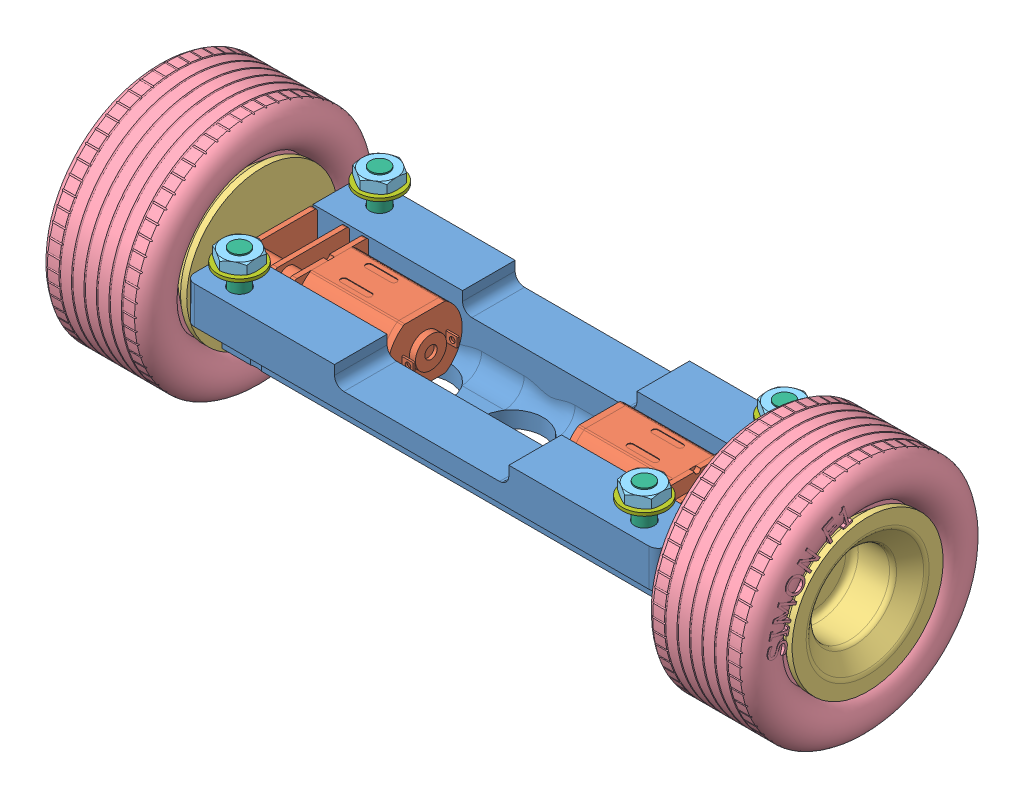
SolidWorks assembly Assembly wiel, configuration Default. Lengths in mm.
Overall size (115.21 38 38).
19 component instances, 7 part files, 51 mates.
Components (placement in the parent):
- Motor mount-1: Motor mount [Default] at origin size (76 12.7 29)
- Micro Metal Gear Motor-1: Micro Metal Gear Motor [Default] at (29 -5.04 0) x (0 0 -1) z (1 0 0) size (12 10 35.9)
- Micro Metal Gear Motor-2: Micro Metal Gear Motor [Default] at (-29 -5.04 0) x (0 0 1) z (-1 0 0) size (12 10 35.9)
- Velg-1: Velg [Default] at (-48.6 -5.04 0) x (1 0 0) z (0 -1 0) size (17 24.25 24.25)
- Velg-2: Velg [Default] at (48.6 -5.04 0) x (-1 0 0) z (0 -1 0) size (17 24.25 24.25)
- Band-1: Band [Default] at (48.6 -5.04 0) x (1 0 0) z (0 1 0) size (18 38 38)
- Band-2: Band [Default] at (-48.6 -5.04 0) x (-1 0 0) z (0 1 0) size (18 38 38)
- hex thin nut chamfered gradeab_iso-1: hex thin nut chamfered gradeab_iso [ISO - 4035 - M3 - N] at (32.5 5.3 -11.25) x (0.5 0 0.866025) z (0 1 0) size (5.5 6.35 1.8)
- hex thin nut chamfered gradeab_iso-2: hex thin nut chamfered gradeab_iso [ISO - 4035 - M3 - N] at (-32.5 5.3 11.25) x (0.5 0 -0.866025) z (0 1 0) size (5.5 6.35 1.8)
- pan head cross recess screw_iso-1: pan head cross recess screw_iso [ISO 7045 - M3 x 10 - Z - 10N] at (32.5 -6.9 11.25) x (0 1 0) z (-1 0 0) size (12.35 5.6 5.6)
- pan head cross recess screw_iso-2: pan head cross recess screw_iso [ISO 7045 - M3 x 10 - Z - 10N] at (32.5 -6.9 -11.25) x (0 1 0) z (-1 0 0) size (12.35 5.6 5.6)
- pan head cross recess screw_iso-3: pan head cross recess screw_iso [ISO 7045 - M3 x 10 - Z - 10N] at (-32.5 -6.9 11.25) x (0 1 0) z (-1 0 0) size (12.35 5.6 5.6)
- pan head cross recess screw_iso-4: pan head cross recess screw_iso [ISO 7045 - M3 x 10 - Z - 10N] at (-32.5 -6.9 -11.25) x (0 1 0) z (-1 0 0) size (12.35 5.6 5.6)
- hex thin nut chamfered gradeab_iso-3: hex thin nut chamfered gradeab_iso [ISO - 4035 - M3 - N] at (-32.5 5.3 -11.25) x (-0.5 0 -0.866025) z (0 1 0) size (5.5 6.35 1.8)
- hex thin nut chamfered gradeab_iso-4: hex thin nut chamfered gradeab_iso [ISO - 4035 - M3 - N] at (32.5 3.5 11.25) x (1 0 0) z (0 -1 0) size (5.5 6.35 1.8)
- plain washer normal grade a_iso-1: plain washer normal grade a_iso [Washer ISO 7089 - 3] at (32.5 3 -11.25) x (0 -1 0) z (-1 0 0) size (0.5 7 7)
- plain washer normal grade a_iso-2: plain washer normal grade a_iso [Washer ISO 7089 - 3] at (32.5 3 11.25) x (0 -1 0) z (-1 0 0) size (0.5 7 7)
- plain washer normal grade a_iso-3: plain washer normal grade a_iso [Washer ISO 7089 - 3] at (-32.5 3 11.25) x (0 -1 0) z (-1 0 0) size (0.5 7 7)
- plain washer normal grade a_iso-4: plain washer normal grade a_iso [Washer ISO 7089 - 3] at (-32.5 3 -11.25) x (0 -1 0) z (-1 0 0) size (0.5 7 7)
Mates (geometry in assembly coordinates):
- Coincident32: coincident aligned: plane of Motor mount-1 through (0 0 0) normal (1 0 0)
- Coincident33: coincident aligned: plane of Motor mount-1 through (0 0 0) normal (0 0 1)
- Coincident35: coincident aligned: plane of Motor mount-1 through (0 0 0) normal (0 1 0)
- Concentric17: concentric aligned: cylinder of Motor mount-1 through (32.5 0 -11.25) axis (0 -1 0) radius 1.5875; cylinder of pan head cross recess screw_iso-2 through (32.5 -32.3 -11.25) axis (0 -1 0) radius 1.5
- Concentric18: concentric aligned: cylinder of Motor mount-1 through (32.5 0 11.25) axis (0 -1 0) radius 1.5875; cylinder of pan head cross recess screw_iso-1 through (32.5 -32.3 11.25) axis (0 -1 0) radius 1.5
- Concentric19: concentric aligned: cylinder of Motor mount-1 through (-32.5 0 11.25) axis (0 -1 0) radius 1.5875; cylinder of pan head cross recess screw_iso-3 through (-32.5 -32.3 11.25) axis (0 -1 0) radius 1.5
- Concentric20: concentric aligned: cylinder of Motor mount-1 through (-32.5 0 -11.25) axis (0 -1 0) radius 1.5875; cylinder of pan head cross recess screw_iso-4 through (-32.5 -32.3 -11.25) axis (0 -1 0) radius 1.5
- Coincident36: coincident aligned: plane of pan head cross recess screw_iso-1 through (32.5 -4.5 9.75) normal (0 1 0); plane of pan head cross recess screw_iso-2 through (32.5 -4.5 -12.75) normal (0 1 0)
- Coincident37: coincident aligned: plane of pan head cross recess screw_iso-1 through (32.5 -4.5 9.75) normal (0 1 0); plane of pan head cross recess screw_iso-3 through (-32.5 -4.5 9.75) normal (0 1 0)
- Coincident38: coincident aligned: plane of pan head cross recess screw_iso-2 through (32.5 -4.5 -12.75) normal (0 1 0); plane of pan head cross recess screw_iso-4 through (-32.5 -4.5 -12.75) normal (0 1 0)
- Coincident39: coincident aligned: plane of pan head cross recess screw_iso-1 through (32.13 -5.15 11.7775) normal (1 0 0); plane of pan head cross recess screw_iso-2 through (32.13 -5.15 -10.7225) normal (1 0 0)
- Coincident40: coincident aligned: plane of pan head cross recess screw_iso-3 through (-32.87 -5.15 11.7775) normal (1 0 0); plane of pan head cross recess screw_iso-4 through (-32.87 -5.15 -10.7225) normal (1 0 0)
- Coincident41: coincident anti-aligned: plane of Motor mount-1 through (-32.5 -4.5 -11.25) normal (0 -1 0); plane of pan head cross recess screw_iso-4 through (-32.5 -4.5 -12.75) normal (0 1 0)
- Coincident42: coincident aligned: plane of hex thin nut chamfered gradeab_iso-1 through (35.25 3.5 -12.8377) normal (0 -1 0); plane of hex thin nut chamfered gradeab_iso-4 through (32.5 3.5 14.4254) normal (0 -1 0)
- Coincident43: coincident aligned: plane of hex thin nut chamfered gradeab_iso-1 through (35.25 3.5 -12.8377) normal (0 -1 0); plane of hex thin nut chamfered gradeab_iso-2 through (-35.25 3.5 9.6623) normal (0 -1 0)
- Coincident44: coincident aligned: plane of hex thin nut chamfered gradeab_iso-2 through (-35.25 3.5 9.6623) normal (0 -1 0); plane of hex thin nut chamfered gradeab_iso-3 through (-35.25 3.5 -9.6623) normal (0 -1 0)
- Coincident45: coincident aligned: plane of hex thin nut chamfered gradeab_iso-1 through (29.75 3.5 -12.8377) normal (-1 0 0); plane of hex thin nut chamfered gradeab_iso-4 through (29.75 5.3 12.8377) normal (-1 0 0)
- Coincident46: coincident aligned: plane of hex thin nut chamfered gradeab_iso-2 through (-35.25 3.5 9.6623) normal (-1 0 0); plane of hex thin nut chamfered gradeab_iso-3 through (-35.25 3.5 -12.8377) normal (-1 0 0)
- Concentric21: concentric aligned: cylinder of pan head cross recess screw_iso-1 through (32.5 -32.3 11.25) axis (0 -1 0) radius 1.5; cylinder of hex thin nut chamfered gradeab_iso-4 through (32.5 5.3 11.25) axis (0 -1 0) radius 1.25
- Concentric22: concentric anti-aligned: cylinder of hex thin nut chamfered gradeab_iso-1 through (32.5 3.5 -11.25) axis (0 1 0) radius 1.25; cylinder of pan head cross recess screw_iso-2 through (32.5 -32.3 -11.25) axis (0 -1 0) radius 1.5
- Concentric23: concentric anti-aligned: cylinder of hex thin nut chamfered gradeab_iso-2 through (-32.5 3.5 11.25) axis (0 1 0) radius 1.25; cylinder of pan head cross recess screw_iso-3 through (-32.5 -32.3 11.25) axis (0 -1 0) radius 1.5
- Concentric24: concentric anti-aligned: cylinder of pan head cross recess screw_iso-4 through (-32.5 -32.3 -11.25) axis (0 -1 0) radius 1.5; cylinder of hex thin nut chamfered gradeab_iso-3 through (-32.5 3.5 -11.25) axis (0 1 0) radius 1.25
- Coincident48: coincident aligned: plane of plain washer normal grade a_iso-2 through (32.5 3.5 14.75) normal (0 1 0); plane of plain washer normal grade a_iso-3 through (-32.5 3.5 14.75) normal (0 1 0)
- Coincident49: coincident aligned: plane of plain washer normal grade a_iso-1 through (32.5 3.5 -7.75) normal (0 1 0); plane of plain washer normal grade a_iso-4 through (-32.5 3.5 -7.75) normal (0 1 0)
- Coincident50: coincident aligned: plane of plain washer normal grade a_iso-1 through (32.5 3 -11.25) normal (-1 0 0); plane of plain washer normal grade a_iso-2 through (32.5 3 11.25) normal (-1 0 0)
- Coincident51: coincident aligned: plane of plain washer normal grade a_iso-3 through (-32.5 3 11.25) normal (-1 0 0); plane of plain washer normal grade a_iso-4 through (-32.5 3 -11.25) normal (-1 0 0)
- Coincident52: coincident aligned: plane of plain washer normal grade a_iso-3 through (-32.5 3.5 14.75) normal (0 1 0); plane of plain washer normal grade a_iso-4 through (-32.5 3.5 -7.75) normal (0 1 0)
- Concentric25: concentric anti-aligned: cylinder of pan head cross recess screw_iso-3 through (-32.5 -32.3 11.25) axis (0 -1 0) radius 1.5; cylinder of plain washer normal grade a_iso-3 through (-32.5 37.925 11.25) axis (0 1 0) radius 1.6
- Concentric26: concentric anti-aligned: cylinder of pan head cross recess screw_iso-4 through (-32.5 -32.3 -11.25) axis (0 -1 0) radius 1.5; cylinder of plain washer normal grade a_iso-4 through (-32.5 37.925 -11.25) axis (0 1 0) radius 1.6
- Concentric27: concentric anti-aligned: cylinder of pan head cross recess screw_iso-1 through (32.5 -32.3 11.25) axis (0 -1 0) radius 1.5; cylinder of plain washer normal grade a_iso-2 through (32.5 37.925 11.25) axis (0 1 0) radius 1.6
- Concentric28: concentric anti-aligned: cylinder of pan head cross recess screw_iso-2 through (32.5 -32.3 -11.25) axis (0 -1 0) radius 1.5; cylinder of plain washer normal grade a_iso-1 through (32.5 37.925 -11.25) axis (0 1 0) radius 1.6
- Distance2: distance = 3 mm anti-aligned: plane of plain washer normal grade a_iso-3 through (-32.5 3 12.85) normal (0 -1 0); plane of Motor mount-1 through (38 0 14.5) normal (0 1 0)
- Coincident54: coincident anti-aligned: plane of hex thin nut chamfered gradeab_iso-3 through (-35.25 3.5 -9.6623) normal (0 -1 0); plane of plain washer normal grade a_iso-4 through (-32.5 3.5 -7.75) normal (0 1 0)
- Concentric29: concentric anti-aligned: cylinder of Micro Metal Gear Motor-1 through (48.1 -5.04 0) axis (-1 0 0) radius 1.5; cylinder of Micro Metal Gear Motor-2 through (-48.1 -5.04 0) axis (1 0 0) radius 1.5
- Coincident55: coincident aligned: plane of Motor mount-1 through (38 0 0) normal (1 0 0); plane of Micro Metal Gear Motor-1 through (38 -9.54 5.5) normal (1 0 0)
- Coincident56: coincident aligned: plane of Motor mount-1 through (-38 0 0) normal (-1 0 0); plane of Micro Metal Gear Motor-2 through (-38 -9.54 -5.5) normal (-1 0 0)
- Coincident62: coincident aligned: plane of Micro Metal Gear Motor-2 through (-29 -5.04 0) normal (0 0 1)
- Coincident63: coincident: point of Motor mount-1; plane of Micro Metal Gear Motor-2 through (-29 -5.04 0) normal (0 1 0)
- Coincident64: coincident aligned: plane of Micro Metal Gear Motor-1 through (48.1 -4.04 6) normal (0 1 0); plane of Micro Metal Gear Motor-2 through (-48.1 -4.04 -6) normal (0 1 0)
- Concentric30: concentric anti-aligned: cylinder of Velg-1 through (-56.6 -5.04 0) axis (1 0 0) radius 1.65; cylinder of Velg-2 through (56.6 -5.04 0) axis (-1 0 0) radius 1.65
- Coincident66: coincident aligned: plane of Velg-1 through (-40.1 -4.14 -1.3829) normal (0 -1 0); plane of Velg-2 through (40.1 -4.14 1.3829) normal (0 -1 0)
- Concentric31: concentric aligned: cylinder of Micro Metal Gear Motor-1 through (48.1 -5.04 0) axis (-1 0 0) radius 1.5; cylinder of Velg-2 through (56.6 -5.04 0) axis (-1 0 0) radius 1.65
- Parallel4: parallel anti-aligned: plane of Micro Metal Gear Motor-1 through (48.1 -4.04 6) normal (0 1 0); plane of Velg-2 through (40.1 -4.14 1.3829) normal (0 -1 0)
- Coincident68: coincident aligned: plane of Micro Metal Gear Motor-1 through (48.1 -5.04 0) normal (1 0 0); plane of Velg-2 through (48.1 -5.04 -6.5) normal (1 0 0)
- Coincident69: coincident aligned: plane of Micro Metal Gear Motor-2 through (-48.1 -5.04 0) normal (-1 0 0); plane of Velg-1 through (-48.1 -5.04 6.5) normal (-1 0 0)
- Concentric32: concentric anti-aligned: cylinder of Band-1 through (48.6 -5.04 0) axis (1 0 0) radius 18; cylinder of Band-2 through (-48.6 -5.04 0) axis (-1 0 0) radius 18
- Concentric33: concentric anti-aligned: cylinder of Velg-1 through (-50.225 -5.04 0) axis (1 0 0) radius 12; cylinder of Band-2 through (-48.6 -5.04 0) axis (-1 0 0) radius 18
- Coincident70: coincident anti-aligned: plane of Velg-2 through (48.6 -5.04 0) normal (-1 0 0); plane of Band-1 through (48.6 -5.04 0) normal (1 0 0)
- Coincident71: coincident aligned: plane of Velg-2 through (48.6 -5.04 0) normal (0 0 -1); plane of Band-1 through (48.6 -5.04 0) normal (0 0 -1)
- Coincident72: coincident anti-aligned: plane of Velg-1 through (-48.6 -5.04 0) normal (1 0 0); plane of Band-2 through (-48.6 -5.04 0) normal (-1 0 0)
- Coincident73: coincident aligned: plane of Velg-1 through (-48.6 -5.04 0) normal (0 0 1); plane of Band-2 through (-48.6 -5.04 0) normal (0 0 1)
